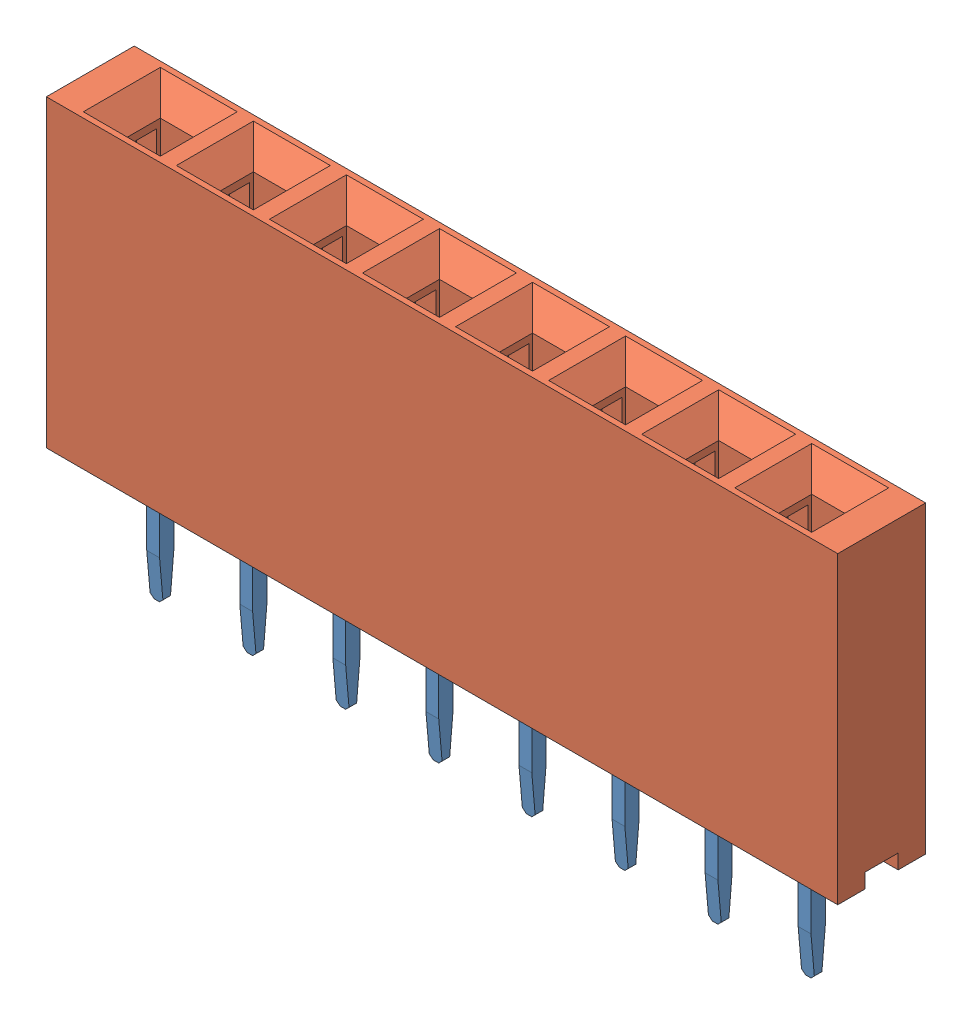
SolidWorks assembly 2_54_x_8_, configuration Default. Lengths in mm.
Overall size (21.6 11.5 2.4).
2 component instances, 2 part files, 8 mates.
Components (placement in the parent):
- Pitch_x_n-1: Pitch_x_n [Default] at origin size (19.73 8.86 0.39)
- Plastic_x_8-1: Plastic_x_8 [Default] x (1 0 0) z (0 1 0) size (21.6 2.4 8.3)
Mates (geometry in assembly coordinates):
- На месте1: in place: plane of Pitch_x_n-1 through (0 0 0) normal (0 0 1); moOrthogonalPlaneRef_w of Pitch_x_n-1 through (0 0 0) normal (0 1 0); plane of Pitch_x_n-1 through (0 0 0) normal (1 0 0); unknown of Pitch_x_n-1
- Совпадение1: coincident aligned: 
- Совпадение2: coincident aligned: plane of Pitch_x_n-1 through (0 0 0) normal (0 1 0)
- Совпадение3: coincident anti-aligned: plane of Pitch_x_n-1 through (0 0 0) normal (1 0 0)
- На месте2: in place: plane of Plastic_x_8-1 through (0 0 0) normal (0 1 0); plane of Plastic_x_8-1 through (0 0 0) normal (0 0 -1); plane of Plastic_x_8-1 through (0 0 0) normal (1 0 0); unknown of Plastic_x_8-1
- Совпадение4: coincident aligned: 
- Совпадение5: coincident aligned: plane of Plastic-1 through (0 0 0) normal (0 0 -1)
- Совпадение6: coincident anti-aligned: plane of Plastic-1 through (0 0 0) normal (1 0 0)
